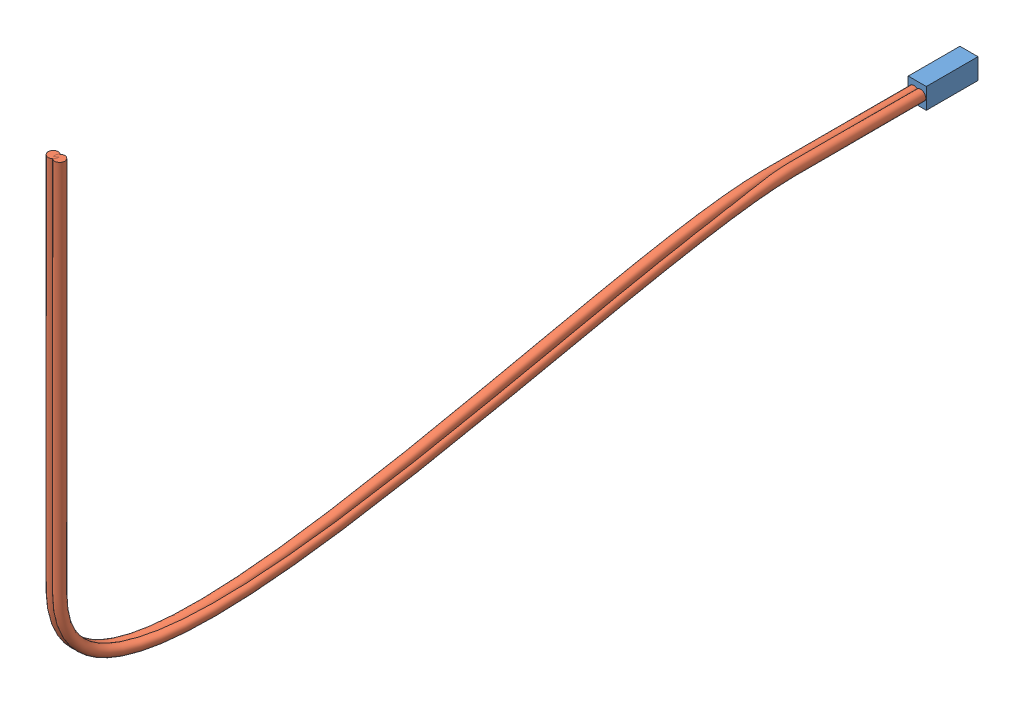
SolidWorks assembly Harness_4-CABLE_HARNESSING_ASSEMBLY, configuration Default. Lengths in mm.
Overall size (35.8 87.81 147.65).
3 component instances, 3 part files, 0 mates.
Components (placement in the parent):
- 02_PIN-1: 02_PIN [Default] at (5.9755 -0.2863 -123.4553) size (3.5 4 20)
- Cable^Harness_4-CABLE_HARNESSING_ASSEMBLY-1: Cable^Harness_4-CABLE_HARNESSING_ASSEMBLY [Default] at origin size (35.8 87.81 138.4) (virtual)
- Flattened_Cable^Harness_4-CABLE_HARNESSING_ASSEMBLY-1: Flattened_Cable^Harness_4-CABLE_HARNESSING_ASSEMBLY [Default] at origin (suppressed, hidden, virtual)
